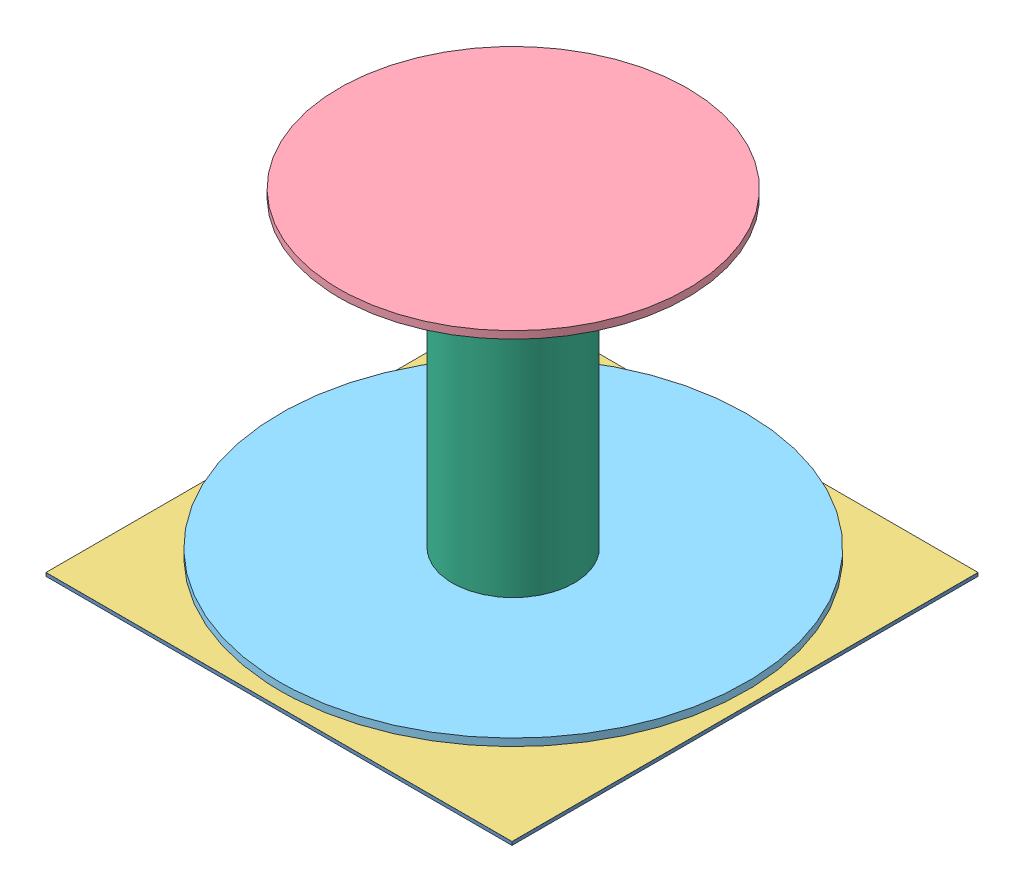
SolidWorks assembly Half Wavelength Antenna, configuration Default. Lengths in mm.
Overall size (107.13 76.98 107.42).
6 component instances, 6 part files, 8 mates.
Components (placement in the parent):
- Dielectric-1: Dielectric [Default] at (-102.7945 24.675 203.7416) size (107.07 0.76 107.07)
- Feed Network-1: Feed Network [Default] at (-102.7945 24.655 143.2016) size (96.87 0.02 42.99)
- Ground Plane-1: Ground Plane [Default] at (-102.7945 25.437 203.7416) size (107.07 0.02 107.07)
- Parasitic SAP-1: Parasitic SAP [Default] at (-49.3237 99.935 149.857) size (80 1.7 80)
- SAP-1: SAP [Default] at (-49.3237 28.437 149.857) size (107.07 1.7 107.07)
- Tower-1: Tower [Default] at (-49.3237 25.437 149.857) size (28 74.5 28)
Mates (geometry in assembly coordinates):
- Coincident3: coincident: point of Dielectric-1; point of Ground Plane-1
- Coincident5: coincident anti-aligned: plane of Parasitic SAP-1 through (-49.3237 99.935 149.857) normal (0 -1 0); plane of Tower-1 through (-49.3237 99.935 149.857) normal (0 1 0)
- Concentric1: concentric aligned: circle of Parasitic SAP-1; circle of Tower-1
- Concentric3: concentric aligned: cylinder of SAP-1 through (-49.3237 30.137 149.857) axis (0 -1 0) radius 14; cylinder of Tower-1 through (-49.3237 99.935 149.857) axis (0 -1 0) radius 14
- Distance3: distance = 3 mm aligned: plane of SAP-1 through (-49.3237 28.437 149.857) normal (0 -1 0); plane of Tower-1 through (-49.3237 25.437 149.857) normal (0 -1 0)
- Concentric6: concentric aligned: circle of Ground Plane-1; circle of Tower-1
- Coincident11: coincident: line of Dielectric-1 through (-102.7945 24.675 96.6716) axis (0 0 1); line of Feed Network-1 through (-102.7945 24.675 141.1716) axis (0 0 1)
- Distance4: distance = 44.53 mm: point of Feed Network-1; point of Dielectric-1
